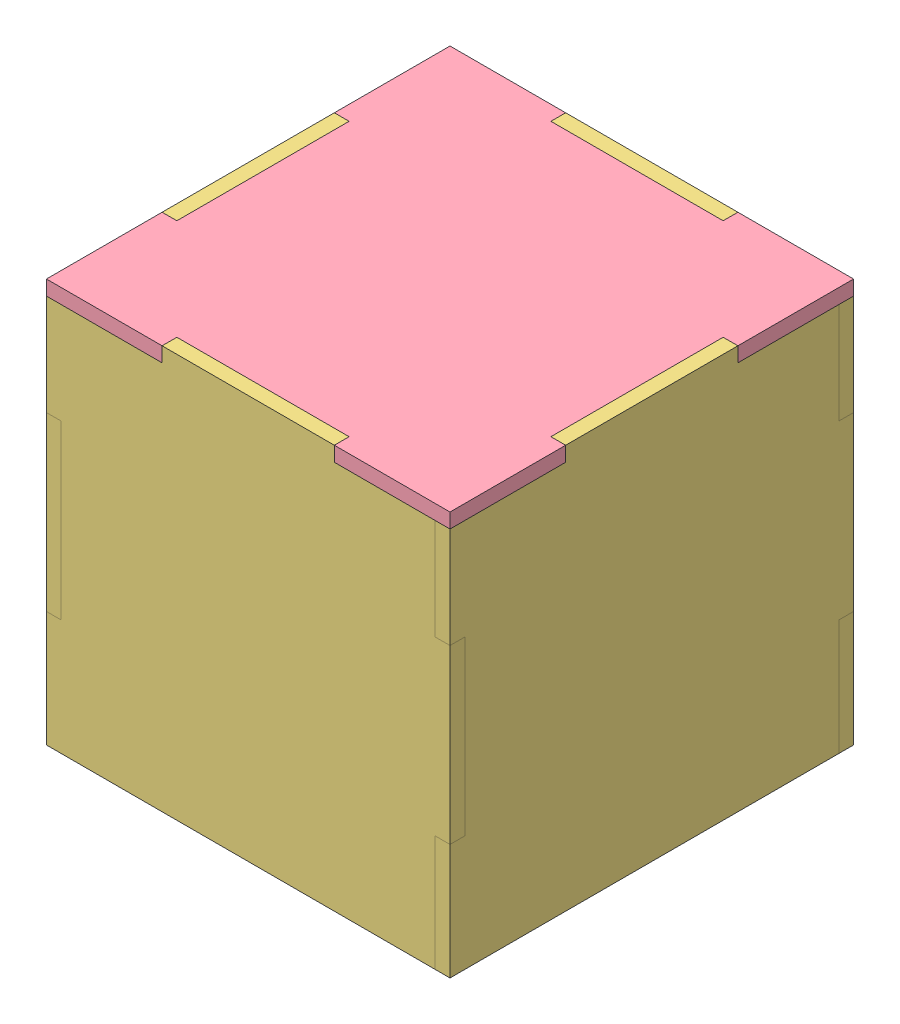
SolidWorks assembly Assembly, configuration Default. Lengths in mm.
Overall size (82 82 82).
10 component instances, 4 part files, 27 mates.
Components (placement in the parent):
- Bottom_Face-1: Bottom_Face [Default] at (37.0971 34.7074 56.077) size (76 3 76)
- Inner_Side_Face-1: Inner_Side_Face [Default] at (37.0971 75.7074 91.077) size (76 79 3)
- Inner_Side_Face-2: Inner_Side_Face [Default] at (72.0971 75.7074 56.077) x (0 0 -1) z (1 0 0) size (76 79 3)
- Inner_Side_Face-3: Inner_Side_Face [Default] at (37.0971 75.7074 21.077) x (-1 0 0) z (0 0 -1) size (76 79 3)
- Inner_Side_Face-4: Inner_Side_Face [Default] at (2.0971 75.7074 56.077) x (0 0 1) z (-1 0 0) size (76 79 3)
- Outer_Side_Face-1: Outer_Side_Face [Default] at (37.0971 74.2074 94.077) size (82 82 3)
- Outer_Side_Face-2: Outer_Side_Face [Default] at (75.0971 74.2074 56.077) x (0 0 -1) z (1 0 0) size (82 82 3)
- Outer_Side_Face-3: Outer_Side_Face [Default] at (37.0971 74.2074 18.077) x (-1 0 0) z (0 0 -1) size (82 82 3)
- Outer_Side_Face-4: Outer_Side_Face [Default] at (-0.9029 74.2074 56.077) x (0 0 1) z (-1 0 0) size (82 82 3)
- Top_Face-1: Top_Face [Default] at (37.0971 113.7074 56.077) size (82 3 82)
Mates (geometry in assembly coordinates):
- Coincident1: coincident: plane of Bottom_Face-1 through (19.5971 37.7074 94.077) normal (0 0 1); plane of Inner_Side_Face-1 through (37.0971 75.7074 94.077) normal (0 0 1)
- Coincident2: coincident: plane of Bottom_Face-1 through (37.0971 37.7074 56.077) normal (0 1 0); plane of Inner_Side_Face-1 through (19.5971 37.7074 94.077) normal (0 -1 0)
- Coincident3: coincident: plane of Bottom_Face-1 through (19.5971 37.7074 94.077) normal (-1 0 0); plane of Inner_Side_Face-1 through (19.5971 37.7074 94.077) normal (1 0 0)
- Coincident4: coincident: plane of Bottom_Face-1 through (72.0971 37.7074 91.077) normal (1 0 0); plane of Inner_Side_Face-2 through (72.0971 75.7074 56.077) normal (-1 0 0)
- Coincident5: coincident: plane of Inner_Side_Face-1 through (37.0971 75.7074 91.077) normal (0 0 -1); plane of Inner_Side_Face-2 through (75.0971 96.2074 91.077) normal (0 0 1)
- Coincident6: coincident: plane of Bottom_Face-1 through (37.0971 37.7074 56.077) normal (0 1 0); plane of Inner_Side_Face-2 through (75.0971 37.7074 73.577) normal (0 -1 0)
- Coincident7: coincident: plane of Bottom_Face-1 through (19.5971 37.7074 18.077) normal (0 0 -1); plane of Inner_Side_Face-3 through (37.0971 75.7074 18.077) normal (0 0 -1)
- Coincident8: coincident: plane of Inner_Side_Face-2 through (72.0971 75.7074 56.077) normal (-1 0 0); plane of Inner_Side_Face-3 through (72.0971 96.2074 18.077) normal (1 0 0)
- Coincident9: coincident: plane of Bottom_Face-1 through (37.0971 37.7074 56.077) normal (0 1 0); plane of Inner_Side_Face-3 through (54.5971 37.7074 18.077) normal (0 -1 0)
- Coincident10: coincident: plane of Bottom_Face-1 through (-0.9029 37.7074 73.577) normal (-1 0 0); plane of Inner_Side_Face-4 through (-0.9029 75.7074 56.077) normal (-1 0 0)
- Coincident11: coincident: plane of Inner_Side_Face-3 through (37.0971 75.7074 21.077) normal (0 0 1); plane of Inner_Side_Face-4 through (-0.9029 96.2074 21.077) normal (0 0 -1)
- Coincident12: coincident: plane of Bottom_Face-1 through (37.0971 37.7074 56.077) normal (0 1 0); plane of Inner_Side_Face-4 through (-0.9029 37.7074 38.577) normal (0 -1 0)
- Coincident13: coincident: plane of Inner_Side_Face-1 through (37.0971 75.7074 94.077) normal (0 0 1); plane of Outer_Side_Face-1 through (37.0971 74.2074 94.077) normal (0 0 -1)
- Coincident14: coincident: plane of Bottom_Face-1 through (37.0971 34.7074 56.077) normal (0 -1 0); plane of Outer_Side_Face-1 through (-3.9029 34.7074 97.077) normal (0 -1 0)
- Coincident15: coincident: plane of Inner_Side_Face-2 through (75.0971 75.7074 56.077) normal (1 0 0); plane of Outer_Side_Face-1 through (75.0971 55.2074 97.077) normal (1 0 0)
- Coincident16: coincident: plane of Inner_Side_Face-2 through (75.0971 75.7074 56.077) normal (1 0 0); plane of Outer_Side_Face-2 through (75.0971 74.2074 56.077) normal (-1 0 0)
- Coincident17: coincident: plane of Outer_Side_Face-1 through (37.0971 74.2074 94.077) normal (0 0 -1); plane of Outer_Side_Face-2 through (78.0971 90.2074 94.077) normal (0 0 1)
- Coincident18: coincident: plane of Bottom_Face-1 through (37.0971 34.7074 56.077) normal (0 -1 0); plane of Outer_Side_Face-2 through (78.0971 34.7074 97.077) normal (0 -1 0)
- Coincident19: coincident: plane of Inner_Side_Face-3 through (37.0971 75.7074 18.077) normal (0 0 -1); plane of Outer_Side_Face-3 through (37.0971 74.2074 18.077) normal (0 0 1)
- Coincident20: coincident: plane of Outer_Side_Face-2 through (75.0971 74.2074 56.077) normal (-1 0 0); plane of Outer_Side_Face-3 through (75.0971 90.2074 15.077) normal (1 0 0)
- Coincident21: coincident: plane of Bottom_Face-1 through (37.0971 34.7074 56.077) normal (0 -1 0); plane of Outer_Side_Face-3 through (78.0971 34.7074 15.077) normal (0 -1 0)
- Coincident22: coincident: plane of Inner_Side_Face-4 through (-0.9029 75.7074 56.077) normal (-1 0 0); plane of Outer_Side_Face-4 through (-0.9029 74.2074 56.077) normal (1 0 0)
- Coincident23: coincident: plane of Outer_Side_Face-3 through (37.0971 74.2074 18.077) normal (0 0 1); plane of Outer_Side_Face-4 through (-3.9029 90.2074 18.077) normal (0 0 -1)
- Coincident24: coincident: plane of Bottom_Face-1 through (37.0971 34.7074 56.077) normal (0 -1 0); plane of Outer_Side_Face-4 through (-3.9029 34.7074 15.077) normal (0 -1 0)
- Coincident25: coincident: plane of Outer_Side_Face-1 through (37.0971 74.2074 94.077) normal (0 0 -1); plane of Top_Face-1 through (54.5971 116.7074 94.077) normal (0 0 1)
- Coincident26: coincident: plane of Outer_Side_Face-4 through (-0.9029 74.2074 56.077) normal (1 0 0); plane of Top_Face-1 through (-0.9029 116.7074 38.577) normal (-1 0 0)
- Coincident27: coincident: plane of Outer_Side_Face-4 through (-3.9029 113.7074 15.077) normal (0 1 0); plane of Top_Face-1 through (37.0971 113.7074 56.077) normal (0 -1 0)
